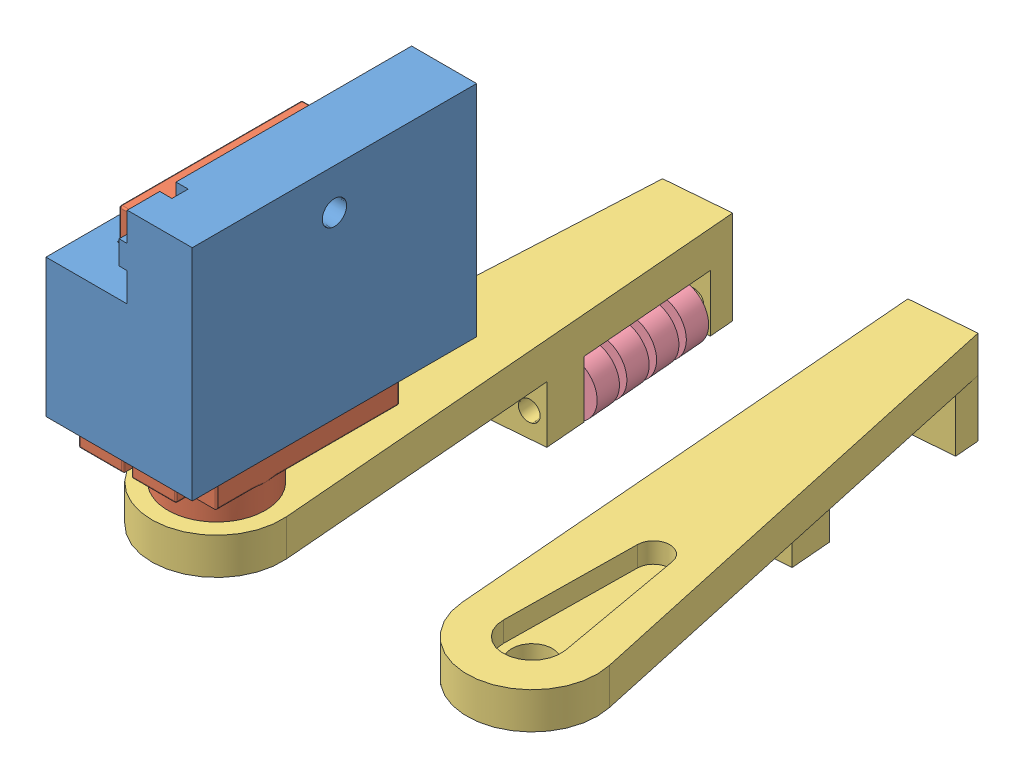
SolidWorks assembly Arm2019RightAssembly, configuration Default. Lengths in mm.
Overall size (57.39 47.54 75.4).
7 component instances, 4 part files, 7 mates.
Components (placement in the parent):
- MG90s_servoSupport2-1: MG90s_servoSupport2 [Default] at (10.4206 7.3143 26.5287) size (18 27 35)
- MG90s_servo-1: MG90s_servo [Default] at (10.4206 7.3143 26.7787) x (0 0 1) z (0 1 0) size (32.5 12 34)
- Arm2019_MG90S-1: Arm2019_MG90S [Default] at (10.4206 -3.6857 32.0287) x (-0.081855 0 -0.996644) z (0 1 0) size (68 52 11.5)
- Sodial7mmx3mmx3mm-1: Sodial7mmx3mmx3mm [Default] at (13.1262 -9.6857 -8.3282) x (-0.996576 0.01173 0.08185) z (-0.081855 0 -0.996644) size (7 7 3)
- Sodial7mmx3mmx3mm-2: Sodial7mmx3mmx3mm [Default] at (12.7988 -9.6857 -12.3148) x (-0.996576 0.01173 0.08185) z (-0.081855 0 -0.996644) size (7 7 3)
- Sodial7mmx3mmx3mm-3: Sodial7mmx3mmx3mm [Default] at (12.4714 -9.6857 -16.3014) x (-0.996576 0.01173 0.08185) z (-0.081855 0 -0.996644) size (7 7 3)
- Sodial7mmx3mmx3mm-6: Sodial7mmx3mmx3mm [Default] at (12.144 -9.6857 -20.288) x (-0.996576 0.01173 0.08185) z (-0.081855 0 -0.996644) size (7 7 3)
Mates (geometry in assembly coordinates):
- Coincident1: coincident anti-aligned: plane of MG90s_servoSupport2-1 through (1.4206 7.3143 44.0287) normal (0 -1 0); plane of MG90s_servo-1 through (10.4206 7.3143 26.7787) normal (0 1 0)
- Concentric1: concentric aligned: cylinder of MG90s_servoSupport2-1 through (10.4206 7.3143 12.7787) axis (0 1 0) radius 1.25; cylinder of MG90s_servo-1 through (10.4206 5.0143 12.7787) axis (0 1 0) radius 1
- Parallel1: parallel aligned: plane of MG90s_servoSupport2-1 through (1.4206 24.3143 44.0287) normal (-1 0 0); plane of MG90s_servo-1 through (4.4206 28.3143 15.5287) normal (-1 0 0)
- Concentric2: concentric anti-aligned: circle of MG90s_servo-1; cylinder of Arm2019_MG90S-1 through (10.4206 -5.6857 32.0287) axis (0 1 0) radius 2.5
- Coincident3: coincident aligned: plane of MG90s_servo-1 through (10.4206 -5.6857 32.0287) normal (0 -1 0); plane of Arm2019_MG90S-1 through (10.4206 -5.6857 32.0287) normal (0 -1 0)
- Concentric3: concentric aligned: circle of Arm2019_MG90S-1; cylinder of Sodial7mmx3mmx3mm-1 through (16.0531 -9.6857 27.3077) axis (0.081855 0 0.996644) radius 1.5
- Distance1: distance = 2 mm anti-aligned: plane of Sodial7mmx3mmx3mm-6 through (11.8984 -9.6857 -23.2779) normal (-0.081855 0 -0.996644); plane of Arm2019_MG90S-1 through (5.7548 -12.6857 -24.7801) normal (0.081855 0 0.996644)
